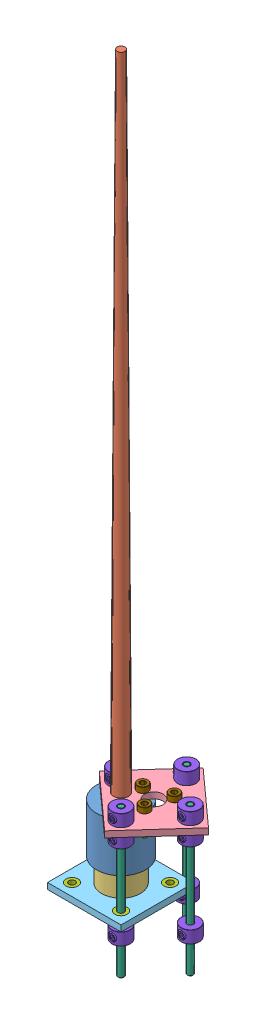
SolidWorks assembly probe_assy, configuration Default. Lengths in mm.
Overall size (57.73 403.23 53.81).
31 component instances, 9 part files, 62 mates.
Components (placement in the parent):
- probe_housing-2: probe_housing [Default] at (-2.0452 29.7766 19.6753) x (0.837297 0 0.546748) z (-0.546748 0 0.837297) size (25.4 25.4 25.4)
- probe_chopstick14in-1: probe_chopstick14in [Default] at (-2.0452 36.1266 19.6753) x (1 0 0) z (0 -1 0) size (8.04 8.04 355.6)
- TAS606-1: TAS606 [Default] at (-2.0452 27.7766 19.6753) size (20 12 20)
- top_plate-2: top_plate [Default] at (9.7318 55.1766 14.4386) x (0.742513 0 0.669832) z (-0.669832 0 0.742513) size (38.1 3.17 38.1)
- bottom_plate-2: bottom_plate [Default] at (-2.0452 14.6016 19.6753) size (38.1 3.17 38.1)
- 1327K930_MINIATURE 12L14 DRIVE STEEL SHAFT-1: 1327K930_MINIATURE 12L14 DRIVE STEEL SHAFT [1327K93] at (10.6548 26.6016 32.3753) x (0.733016 0 -0.680212) z (0 1 0) size (3.17 3.17 76.2)
- 9368T950_HT-TEMP DRY-RUNNING SLEEVE BRNG-1: 9368T950_HT-TEMP DRY-RUNNING SLEEVE BRNG [9368T95] at (10.6548 16.1891 32.3753) x (0.952641 0 -0.304096) z (0 1 0) size (6.35 6.35 3.17)
- 9368T950_HT-TEMP DRY-RUNNING SLEEVE BRNG-2: 9368T950_HT-TEMP DRY-RUNNING SLEEVE BRNG [9368T95] at (10.6548 16.1891 6.9753) x (1 0 0) z (0 1 0) size (6.35 6.35 3.17)
- 9368T950_HT-TEMP DRY-RUNNING SLEEVE BRNG-3: 9368T950_HT-TEMP DRY-RUNNING SLEEVE BRNG [9368T95] at (-14.7452 16.1891 6.9753) x (1 0 0) z (0 1 0) size (6.35 6.35 3.17)
- 9368T950_HT-TEMP DRY-RUNNING SLEEVE BRNG-4: 9368T950_HT-TEMP DRY-RUNNING SLEEVE BRNG [9368T95] at (-14.7452 16.1891 32.3753) x (1 0 0) z (0 1 0) size (6.35 6.35 3.17)
- 1327K930_MINIATURE 12L14 DRIVE STEEL SHAFT-2: 1327K930_MINIATURE 12L14 DRIVE STEEL SHAFT [1327K93] at (-8.205 26.6016 15.3616) x (0.66236 0 -0.749186) z (0 1 0) size (3.17 3.17 76.2)
- 1327K930_MINIATURE 12L14 DRIVE STEEL SHAFT-3: 1327K930_MINIATURE 12L14 DRIVE STEEL SHAFT [1327K93] at (27.6686 26.6016 13.5155) x (0.774411 0 -0.632683) z (0 1 0) size (3.17 3.17 76.2)
- 1327K930_MINIATURE 12L14 DRIVE STEEL SHAFT-4: 1327K930_MINIATURE 12L14 DRIVE STEEL SHAFT [1327K93] at (8.8087 26.6016 -3.4982) x (0.774411 0 -0.632683) z (0 1 0) size (3.17 3.17 76.2)
- 6432K170_SET SCREW SHAFT COLLAR-4: 6432K170_SET SCREW SHAFT COLLAR [6432K17] at (27.6686 61.5266 13.5155) x (1 0 0) z (0 -1 0) size (9.53 9.53 6.35)
- 6432K170_SET SCREW SHAFT COLLAR-5: 6432K170_SET SCREW SHAFT COLLAR [6432K17] at (-8.205 52.0016 15.3616) x (1 0 0) z (0 -1 0) size (9.53 9.53 6.35)
- 6432K170_SET SCREW SHAFT COLLAR-6: 6432K170_SET SCREW SHAFT COLLAR [6432K17] at (8.8087 61.5266 -3.4982) x (0.570557 0 0.821258) z (0 -1 0) size (9.53 9.53 6.35)
- 6432K170_SET SCREW SHAFT COLLAR-7: 6432K170_SET SCREW SHAFT COLLAR [6432K17] at (10.6548 61.5266 32.3753) x (1 0 0) z (0 -1 0) size (9.53 9.53 6.35)
- 6432K170_SET SCREW SHAFT COLLAR-8: 6432K170_SET SCREW SHAFT COLLAR [6432K17] at (10.6548 52.0016 32.3753) x (1 0 0) z (0 -1 0) size (9.53 9.53 6.35)
- 6432K170_SET SCREW SHAFT COLLAR-9: 6432K170_SET SCREW SHAFT COLLAR [6432K17] at (-8.205 61.5266 15.3616) x (1 0 0) z (0 -1 0) size (9.53 9.53 6.35)
- 6432K170_SET SCREW SHAFT COLLAR-10: 6432K170_SET SCREW SHAFT COLLAR [6432K17] at (8.8087 52.0016 -3.4982) x (1 0 0) z (0 -1 0) size (9.53 9.53 6.35)
- 6432K170_SET SCREW SHAFT COLLAR-11: 6432K170_SET SCREW SHAFT COLLAR [6432K17] at (27.6686 52.0016 13.5155) x (1 0 0) z (0 -1 0) size (9.53 9.53 6.35)
- 6432K170_SET SCREW SHAFT COLLAR-12: 6432K170_SET SCREW SHAFT COLLAR [6432K17] at (10.6548 8.4266 32.3753) x (1 0 0) z (0 -1 0) size (9.53 9.53 6.35)
- 6432K170_SET SCREW SHAFT COLLAR-13: 6432K170_SET SCREW SHAFT COLLAR [6432K17] at (8.8087 8.4266 -3.4982) x (0.97365 0 -0.228048) z (0 -1 0) size (9.53 9.53 6.35)
- 6432K170_SET SCREW SHAFT COLLAR-14: 6432K170_SET SCREW SHAFT COLLAR [6432K17] at (27.6686 8.4266 13.5155) x (1 0 0) z (0 -1 0) size (9.53 9.53 6.35)
- 6432K170_SET SCREW SHAFT COLLAR-15: 6432K170_SET SCREW SHAFT COLLAR [6432K17] at (-8.205 8.4266 15.3616) x (1 0 0) z (0 -1 0) size (9.53 9.53 6.35)
- 91290A117_BLACK-OXIDE CLASS 12.9 SOCKET HEAD CAP SCREW-1: 91290A117_BLACK-OXIDE CLASS 12.9 SOCKET HEAD CAP SCREW [91290A117] at (2.3972 46.3516 12.8723) x (0.155334 0 -0.987862) z (0 -1 0) size (5.5 5.5 15.23)
- 91290A117_BLACK-OXIDE CLASS 12.9 SOCKET HEAD CAP SCREW-2: 91290A117_BLACK-OXIDE CLASS 12.9 SOCKET HEAD CAP SCREW [91290A117] at (12.0427 46.3516 21.5737) x (0.98955 0 0.144191) z (0 -1 0) size (5.5 5.5 15.23)
- 91290A117_BLACK-OXIDE CLASS 12.9 SOCKET HEAD CAP SCREW-3: 91290A117_BLACK-OXIDE CLASS 12.9 SOCKET HEAD CAP SCREW [91290A117] at (14.7555 46.3516 8.8697) x (0.977962 0 0.208784) z (0 -1 0) size (5.5 5.5 15.23)
- 91290A117_BLACK-OXIDE CLASS 12.9 SOCKET HEAD CAP SCREW-4: 91290A117_BLACK-OXIDE CLASS 12.9 SOCKET HEAD CAP SCREW [91290A117] at (-2.0452 26.6016 12.1753) x (-0.932913 0 -0.360103) z (0 1 0) size (5.5 5.5 15.23)
- 91290A117_BLACK-OXIDE CLASS 12.9 SOCKET HEAD CAP SCREW-5: 91290A117_BLACK-OXIDE CLASS 12.9 SOCKET HEAD CAP SCREW [91290A117] at (-8.5404 26.6016 23.4253) x (0.353074 0 0.935595) z (0 1 0) size (5.5 5.5 15.23)
- 91290A117_BLACK-OXIDE CLASS 12.9 SOCKET HEAD CAP SCREW-6: 91290A117_BLACK-OXIDE CLASS 12.9 SOCKET HEAD CAP SCREW [91290A117] at (4.45 26.6016 23.4253) x (-0.907285 0 -0.420516) z (0 1 0) size (5.5 5.5 15.23)
Mates (geometry in assembly coordinates):
- Coincident2: coincident anti-aligned: plane of probe_housing-2 through (-2.0452 29.7766 19.6753) normal (0 -1 0); plane of TAS606-1 through (-2.0452 29.7766 19.6753) normal (0 1 0)
- Concentric7: concentric anti-aligned: cylinder of probe_housing-2 through (-2.0452 55.1766 19.6753) axis (0 -1 0) radius 12.7; cylinder of TAS606-1 through (-2.0452 17.7766 19.6753) axis (0 1 0) radius 10
- Coincident3: coincident anti-aligned: plane of probe_housing-2 through (-2.0452 36.1266 19.6753) normal (0 1 0); plane of probe_chopstick14in-1 through (-2.0452 36.1266 19.6753) normal (0 -1 0)
- Concentric8: concentric aligned: cylinder of probe_housing-2 through (-2.0452 36.1266 19.6753) axis (0 1 0) radius 4.075; cone of probe_chopstick14in-1 through (-2.0452 36.1266 19.6753) axis (0 1 0)
- Coincident4: coincident anti-aligned: plane of probe_housing-2 through (-2.0452 55.1766 19.6753) normal (0 1 0); plane of top_plate-2 through (9.7318 55.1766 14.4386) normal (0 -1 0)
- Concentric9: concentric aligned: cylinder of probe_housing-2 through (2.3972 43.1766 12.8723) axis (0 1 0) radius 1.25; cylinder of top_plate-2 through (2.3972 55.1766 12.8723) axis (0 1 0) radius 1.5
- Concentric11: concentric aligned: cylinder of top_plate-2 through (10.6548 55.1766 32.3753) axis (0 1 0) radius 1.5875; cylinder of bottom_plate-2 through (10.6548 14.6016 32.3753) axis (0 1 0) radius 3.175
- Coincident5: coincident anti-aligned: plane of TAS606-1 through (-2.0452 17.7766 19.6753) normal (0 -1 0); plane of bottom_plate-2 through (-2.0452 17.7766 19.6753) normal (0 1 0)
- Concentric12: concentric anti-aligned: cylinder of TAS606-1 through (4.45 22.7766 23.4253) axis (0 -1 0) radius 1.5; cylinder of bottom_plate-2 through (4.45 14.6016 23.4253) axis (0 1 0) radius 1.5
- Concentric13: concentric anti-aligned: cylinder of bottom_plate-2 through (10.6548 14.6016 32.3753) axis (0 1 0) radius 3.175; cylinder of 1327K930_MINIATURE 12L14 DRIVE STEEL SHAFT-1 through (10.6548 64.7016 32.3753) axis (0 -1 0) radius 1.5875
- Concentric14: concentric anti-aligned: cylinder of bottom_plate-2 through (10.6548 14.6016 32.3753) axis (0 1 0) radius 3.175; cylinder of 9368T950_HT-TEMP DRY-RUNNING SLEEVE BRNG-1 through (10.6548 17.7766 32.3753) axis (0 -1 0) radius 3.175
- Coincident6: coincident aligned: plane of bottom_plate-2 through (-2.0452 17.7766 19.6753) normal (0 1 0); plane of 9368T950_HT-TEMP DRY-RUNNING SLEEVE BRNG-1 through (10.6548 17.7766 32.3753) normal (0 1 0)
- Concentric17: concentric anti-aligned: cylinder of bottom_plate-2 through (-14.7452 14.6016 6.9753) axis (0 1 0) radius 3.175; cylinder of 9368T950_HT-TEMP DRY-RUNNING SLEEVE BRNG-3 through (-14.7452 17.7766 6.9753) axis (0 -1 0) radius 3.175
- Concentric18: concentric anti-aligned: cylinder of bottom_plate-2 through (-14.7452 14.6016 32.3753) axis (0 1 0) radius 3.175; cylinder of 9368T950_HT-TEMP DRY-RUNNING SLEEVE BRNG-4 through (-14.7452 17.7766 32.3753) axis (0 -1 0) radius 3.175
- Concentric19: concentric anti-aligned: cylinder of bottom_plate-2 through (10.6548 14.6016 6.9753) axis (0 1 0) radius 3.175; cylinder of 9368T950_HT-TEMP DRY-RUNNING SLEEVE BRNG-2 through (10.6548 17.7766 6.9753) axis (0 -1 0) radius 3.175
- Coincident11: coincident aligned: plane of bottom_plate-2 through (-2.0452 17.7766 19.6753) normal (0 1 0); plane of 9368T950_HT-TEMP DRY-RUNNING SLEEVE BRNG-3 through (-14.7452 17.7766 6.9753) normal (0 1 0)
- Coincident12: coincident aligned: plane of bottom_plate-2 through (-2.0452 17.7766 19.6753) normal (0 1 0); plane of 9368T950_HT-TEMP DRY-RUNNING SLEEVE BRNG-4 through (-14.7452 17.7766 32.3753) normal (0 1 0)
- Coincident13: coincident aligned: plane of bottom_plate-2 through (-2.0452 17.7766 19.6753) normal (0 1 0); plane of 9368T950_HT-TEMP DRY-RUNNING SLEEVE BRNG-2 through (10.6548 17.7766 6.9753) normal (0 1 0)
- Concentric20: concentric anti-aligned: cylinder of top_plate-2 through (8.8087 55.1766 -3.4982) axis (0 1 0) radius 1.5875; cylinder of 1327K930_MINIATURE 12L14 DRIVE STEEL SHAFT-4 through (8.8087 64.7016 -3.4982) axis (0 -1 0) radius 1.5875
- Concentric21: concentric anti-aligned: cylinder of top_plate-2 through (-8.205 55.1766 15.3616) axis (0 1 0) radius 1.5875; cylinder of 1327K930_MINIATURE 12L14 DRIVE STEEL SHAFT-2 through (-8.205 64.7016 15.3616) axis (0 -1 0) radius 1.5875
- Concentric22: concentric anti-aligned: cylinder of top_plate-2 through (27.6686 55.1766 13.5155) axis (0 1 0) radius 1.5875; cylinder of 1327K930_MINIATURE 12L14 DRIVE STEEL SHAFT-3 through (27.6686 64.7016 13.5155) axis (0 -1 0) radius 1.5875
- Coincident14: coincident anti-aligned: plane of top_plate-2 through (9.7318 58.3516 14.4386) normal (0 1 0); plane of 6432K170_SET SCREW SHAFT COLLAR-9 through (-8.205 58.3516 15.3616) normal (0 -1 0)
- Concentric24: concentric anti-aligned: cylinder of 1327K930_MINIATURE 12L14 DRIVE STEEL SHAFT-2 through (-8.205 64.7016 15.3616) axis (0 -1 0) radius 1.5875; cylinder of 6432K170_SET SCREW SHAFT COLLAR-9 through (-8.205 58.3516 15.3616) axis (0 1 0) radius 1.5875
- Coincident15: coincident anti-aligned: plane of top_plate-2 through (9.7318 55.1766 14.4386) normal (0 -1 0); plane of 6432K170_SET SCREW SHAFT COLLAR-5 through (-8.205 55.1766 15.3616) normal (0 1 0)
- Concentric25: concentric anti-aligned: cylinder of 1327K930_MINIATURE 12L14 DRIVE STEEL SHAFT-2 through (-8.205 64.7016 15.3616) axis (0 -1 0) radius 1.5875; cylinder of 6432K170_SET SCREW SHAFT COLLAR-5 through (-8.205 48.8266 15.3616) axis (0 1 0) radius 1.5875
- Coincident16: coincident anti-aligned: plane of top_plate-2 through (9.7318 58.3516 14.4386) normal (0 1 0); plane of 6432K170_SET SCREW SHAFT COLLAR-6 through (8.8087 58.3516 -3.4982) normal (0 -1 0)
- Concentric26: concentric anti-aligned: cylinder of 1327K930_MINIATURE 12L14 DRIVE STEEL SHAFT-4 through (8.8087 64.7016 -3.4982) axis (0 -1 0) radius 1.5875; cylinder of 6432K170_SET SCREW SHAFT COLLAR-6 through (8.8087 58.3516 -3.4982) axis (0 1 0) radius 1.5875
- Concentric27: concentric anti-aligned: cylinder of 1327K930_MINIATURE 12L14 DRIVE STEEL SHAFT-1 through (10.6548 64.7016 32.3753) axis (0 -1 0) radius 1.5875; cylinder of 6432K170_SET SCREW SHAFT COLLAR-7 through (10.6548 58.3516 32.3753) axis (0 1 0) radius 1.5875
- Coincident17: coincident anti-aligned: plane of top_plate-2 through (9.7318 58.3516 14.4386) normal (0 1 0); plane of 6432K170_SET SCREW SHAFT COLLAR-7 through (10.6548 58.3516 32.3753) normal (0 -1 0)
- Coincident18: coincident anti-aligned: plane of top_plate-2 through (9.7318 58.3516 14.4386) normal (0 1 0); plane of 6432K170_SET SCREW SHAFT COLLAR-4 through (27.6686 58.3516 13.5155) normal (0 -1 0)
- Concentric28: concentric anti-aligned: cylinder of 1327K930_MINIATURE 12L14 DRIVE STEEL SHAFT-3 through (27.6686 64.7016 13.5155) axis (0 -1 0) radius 1.5875; cylinder of 6432K170_SET SCREW SHAFT COLLAR-4 through (27.6686 58.3516 13.5155) axis (0 1 0) radius 1.5875
- Concentric29: concentric anti-aligned: cylinder of TAS606-1 through (-8.5404 22.7766 23.4253) axis (0 -1 0) radius 1.5; cylinder of bottom_plate-2 through (-8.5404 14.6016 23.4253) axis (0 1 0) radius 1.5
- Concentric30: concentric anti-aligned: cylinder of 1327K930_MINIATURE 12L14 DRIVE STEEL SHAFT-1 through (10.6548 64.7016 32.3753) axis (0 -1 0) radius 1.5875; cylinder of 6432K170_SET SCREW SHAFT COLLAR-8 through (10.6548 48.8266 32.3753) axis (0 1 0) radius 1.5875
- Coincident19: coincident anti-aligned: plane of top_plate-2 through (9.7318 55.1766 14.4386) normal (0 -1 0); plane of 6432K170_SET SCREW SHAFT COLLAR-8 through (10.6548 55.1766 32.3753) normal (0 1 0)
- Concentric31: concentric anti-aligned: cylinder of 1327K930_MINIATURE 12L14 DRIVE STEEL SHAFT-4 through (8.8087 64.7016 -3.4982) axis (0 -1 0) radius 1.5875; cylinder of 6432K170_SET SCREW SHAFT COLLAR-10 through (8.8087 48.8266 -3.4982) axis (0 1 0) radius 4.7625
- Coincident20: coincident anti-aligned: plane of top_plate-2 through (9.7318 55.1766 14.4386) normal (0 -1 0); plane of 6432K170_SET SCREW SHAFT COLLAR-10 through (8.8087 55.1766 -3.4982) normal (0 1 0)
- Concentric32: concentric anti-aligned: cylinder of 1327K930_MINIATURE 12L14 DRIVE STEEL SHAFT-3 through (27.6686 64.7016 13.5155) axis (0 -1 0) radius 1.5875; cylinder of 6432K170_SET SCREW SHAFT COLLAR-11 through (27.6686 48.8266 13.5155) axis (0 1 0) radius 4.7625
- Coincident21: coincident anti-aligned: plane of top_plate-2 through (9.7318 55.1766 14.4386) normal (0 -1 0); plane of 6432K170_SET SCREW SHAFT COLLAR-11 through (27.6686 55.1766 13.5155) normal (0 1 0)
- Coincident22: coincident aligned: plane of 1327K930_MINIATURE 12L14 DRIVE STEEL SHAFT-2 through (-8.205 64.7016 15.3616) normal (0 1 0); plane of 6432K170_SET SCREW SHAFT COLLAR-9 through (-8.205 64.7016 15.3616) normal (0 1 0)
- Coincident23: coincident aligned: plane of 1327K930_MINIATURE 12L14 DRIVE STEEL SHAFT-1 through (10.6548 64.7016 32.3753) normal (0 1 0); plane of 6432K170_SET SCREW SHAFT COLLAR-7 through (10.6548 64.7016 32.3753) normal (0 1 0)
- Coincident24: coincident aligned: plane of 1327K930_MINIATURE 12L14 DRIVE STEEL SHAFT-3 through (27.6686 64.7016 13.5155) normal (0 1 0); plane of 6432K170_SET SCREW SHAFT COLLAR-4 through (27.6686 64.7016 13.5155) normal (0 1 0)
- Coincident25: coincident aligned: plane of 1327K930_MINIATURE 12L14 DRIVE STEEL SHAFT-4 through (8.8087 64.7016 -3.4982) normal (0 1 0); plane of 6432K170_SET SCREW SHAFT COLLAR-6 through (8.8087 64.7016 -3.4982) normal (0 1 0)
- Concentric33: concentric anti-aligned: cylinder of 1327K930_MINIATURE 12L14 DRIVE STEEL SHAFT-2 through (-8.205 64.7016 15.3616) axis (0 -1 0) radius 1.5875; cylinder of 6432K170_SET SCREW SHAFT COLLAR-15 through (-8.205 5.2516 15.3616) axis (0 1 0) radius 4.7625
- Concentric34: concentric anti-aligned: cylinder of 1327K930_MINIATURE 12L14 DRIVE STEEL SHAFT-1 through (10.6548 64.7016 32.3753) axis (0 -1 0) radius 1.5875; cylinder of 6432K170_SET SCREW SHAFT COLLAR-12 through (10.6548 5.2516 32.3753) axis (0 1 0) radius 4.7625
- Concentric35: concentric anti-aligned: cylinder of 1327K930_MINIATURE 12L14 DRIVE STEEL SHAFT-3 through (27.6686 64.7016 13.5155) axis (0 -1 0) radius 1.5875; cylinder of 6432K170_SET SCREW SHAFT COLLAR-14 through (27.6686 5.2516 13.5155) axis (0 1 0) radius 4.7625
- Concentric36: concentric anti-aligned: cylinder of 1327K930_MINIATURE 12L14 DRIVE STEEL SHAFT-4 through (8.8087 64.7016 -3.4982) axis (0 -1 0) radius 1.5875; cylinder of 6432K170_SET SCREW SHAFT COLLAR-13 through (8.8087 5.2516 -3.4982) axis (0 1 0) radius 4.7625
- Distance1: distance = 3 mm anti-aligned: plane of 6432K170_SET SCREW SHAFT COLLAR-13 through (8.8087 11.6016 -3.4982) normal (0 1 0); plane of bottom_plate-2 through (-2.0452 14.6016 19.6753) normal (0 -1 0)
- Coincident27: coincident aligned: plane of 6432K170_SET SCREW SHAFT COLLAR-13 through (8.8087 11.6016 -3.4982) normal (0 1 0); plane of 6432K170_SET SCREW SHAFT COLLAR-15 through (-8.205 11.6016 15.3616) normal (0 1 0)
- Coincident28: coincident aligned: plane of 6432K170_SET SCREW SHAFT COLLAR-12 through (10.6548 11.6016 32.3753) normal (0 1 0); plane of 6432K170_SET SCREW SHAFT COLLAR-13 through (8.8087 11.6016 -3.4982) normal (0 1 0)
- Coincident29: coincident aligned: plane of 6432K170_SET SCREW SHAFT COLLAR-12 through (10.6548 11.6016 32.3753) normal (0 1 0); plane of 6432K170_SET SCREW SHAFT COLLAR-14 through (27.6686 11.6016 13.5155) normal (0 1 0)
- Concentric37: concentric anti-aligned: cylinder of top_plate-2 through (2.3972 55.1766 12.8723) axis (0 1 0) radius 1.5; cylinder of 91290A117_BLACK-OXIDE CLASS 12.9 SOCKET HEAD CAP SCREW-1 through (2.3972 61.3516 12.8723) axis (0 -1 0) radius 2.75
- Coincident30: coincident anti-aligned: plane of top_plate-2 through (9.7318 58.3516 14.4386) normal (0 1 0); plane of 91290A117_BLACK-OXIDE CLASS 12.9 SOCKET HEAD CAP SCREW-1 through (2.3972 58.3516 12.8723) normal (0 -1 0)
- Concentric38: concentric anti-aligned: cylinder of top_plate-2 through (14.7555 55.1766 8.8697) axis (0 1 0) radius 1.5; cylinder of 91290A117_BLACK-OXIDE CLASS 12.9 SOCKET HEAD CAP SCREW-3 through (14.7555 61.3516 8.8697) axis (0 -1 0) radius 2.75
- Coincident31: coincident anti-aligned: plane of top_plate-2 through (9.7318 58.3516 14.4386) normal (0 1 0); plane of 91290A117_BLACK-OXIDE CLASS 12.9 SOCKET HEAD CAP SCREW-3 through (14.7555 58.3516 8.8697) normal (0 -1 0)
- Coincident32: coincident anti-aligned: plane of top_plate-2 through (9.7318 58.3516 14.4386) normal (0 1 0); plane of 91290A117_BLACK-OXIDE CLASS 12.9 SOCKET HEAD CAP SCREW-2 through (12.0427 58.3516 21.5737) normal (0 -1 0)
- Concentric39: concentric anti-aligned: cylinder of top_plate-2 through (12.0427 55.1766 21.5737) axis (0 1 0) radius 1.5; cylinder of 91290A117_BLACK-OXIDE CLASS 12.9 SOCKET HEAD CAP SCREW-2 through (12.0427 61.3516 21.5737) axis (0 -1 0) radius 2.75
- Coincident33: coincident anti-aligned: plane of bottom_plate-2 through (-2.0452 14.6016 19.6753) normal (0 -1 0); plane of 91290A117_BLACK-OXIDE CLASS 12.9 SOCKET HEAD CAP SCREW-5 through (-8.5404 14.6016 23.4253) normal (0 1 0)
- Coincident34: coincident anti-aligned: plane of bottom_plate-2 through (-2.0452 14.6016 19.6753) normal (0 -1 0); plane of 91290A117_BLACK-OXIDE CLASS 12.9 SOCKET HEAD CAP SCREW-4 through (-2.0452 14.6016 12.1753) normal (0 1 0)
- Coincident35: coincident anti-aligned: plane of bottom_plate-2 through (-2.0452 14.6016 19.6753) normal (0 -1 0); plane of 91290A117_BLACK-OXIDE CLASS 12.9 SOCKET HEAD CAP SCREW-6 through (4.45 14.6016 23.4253) normal (0 1 0)
- Concentric40: concentric aligned: cylinder of bottom_plate-2 through (4.45 14.6016 23.4253) axis (0 1 0) radius 1.5; cylinder of 91290A117_BLACK-OXIDE CLASS 12.9 SOCKET HEAD CAP SCREW-6 through (4.45 11.6016 23.4253) axis (0 1 0) radius 2.75
- Concentric41: concentric aligned: cylinder of bottom_plate-2 through (-2.0452 14.6016 12.1753) axis (0 1 0) radius 1.5; cylinder of 91290A117_BLACK-OXIDE CLASS 12.9 SOCKET HEAD CAP SCREW-4 through (-2.0452 11.6016 12.1753) axis (0 1 0) radius 2.75
- Concentric42: concentric aligned: cylinder of bottom_plate-2 through (-8.5404 14.6016 23.4253) axis (0 1 0) radius 1.5; cylinder of 91290A117_BLACK-OXIDE CLASS 12.9 SOCKET HEAD CAP SCREW-5 through (-8.5404 11.6016 23.4253) axis (0 1 0) radius 2.75
